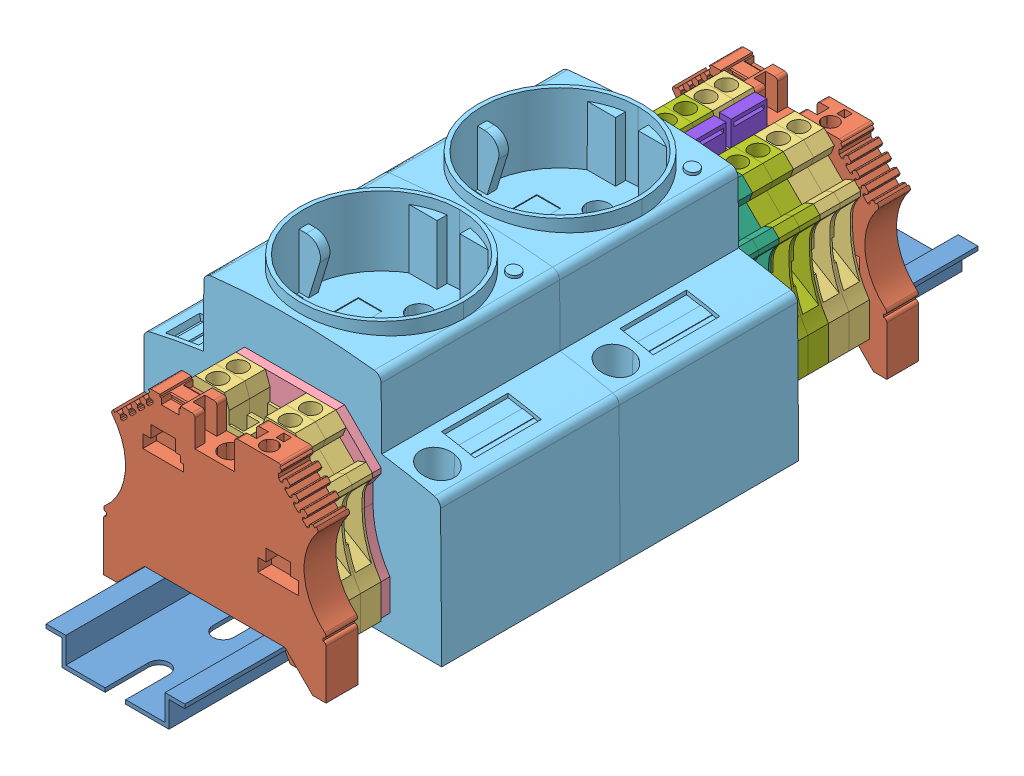
SolidWorks assembly Baugruppe4, configuration Standard. Lengths in mm.
Overall size (75.48 67.56 200).
17 component instances, 8 part files, 51 mates.
Components (placement in the parent):
- Hutschiene-1: Hutschiene [200] at (-17.5 -7.5 -200) size (35 7.5 200)
- WEW_35_2-1: WEW_35_2 [Standard] at (-45.49 -7 -33) x (0 0 1) z (0 1 0) size (8 56.1 46.5)
- UT_2.5-1: UT_2.5 [Standard] at (-48.9989 10.6178 -33) x (0.992546 -0.121869 0) z (0 0 1) size (49.27 50.96 5.15)
- UT_2.5-2: UT_2.5 [Standard] at (-48.9989 10.6178 -38.15) x (0.992546 -0.121869 0) z (0 0 1) size (49.27 50.96 5.15)
- D_UT_2.5_10-1: D_UT_2.5_10 [Standard] at (-46.7297 58.45 -45.5) size (47 39.8 2.2)
- EO_CF_UT_LED-1: EO_CF_UT_LED [Standard] at (-87.6914 -21.0563 -70.25) size (75.48 61.64 45)
- EO_CF_UT_LED-2: EO_CF_UT_LED [Standard] at (-87.6914 -21.0563 -115.25) size (75.48 61.64 45)
- UT_2.5_PE-1: UT_2.5_PE [Standard] at (-48.9989 10.6178 -135.5) x (0.992546 -0.121869 0) z (0 0 1) size (49.27 50.96 5.15)
- UT_2.5_PE-2: UT_2.5_PE [Standard] at (-48.9989 10.6178 -140.65) x (0.992546 -0.121869 0) z (0 0 1) size (49.27 50.96 5.15)
- UT_2.5_BU-1: UT_2.5_BU [Standard] at (-48.9989 10.6178 -145.8) x (0.992546 -0.121869 0) z (0 0 1) size (49.27 50.96 5.15)
- UT_2.5_BU-2: UT_2.5_BU [Standard] at (-48.9989 10.6178 -150.95) x (0.992546 -0.121869 0) z (0 0 1) size (49.27 50.96 5.15)
- UT_2.5-3: UT_2.5 [Standard] at (-48.9989 10.6178 -156.1) x (0.992546 -0.121869 0) z (0 0 1) size (49.27 50.96 5.15)
- UT_2.5-4: UT_2.5 [Standard] at (-48.9989 10.6178 -161.25) x (0.992546 -0.121869 0) z (0 0 1) size (49.27 50.96 5.15)
- WEW_35_2-2: WEW_35_2 [Standard] at (-45.49 -7 -174.4) x (0 0 1) z (0 1 0) size (8 56.1 46.5)
- FBS_2-5-1: FBS_2-5 [Standard] at (-24.4072 49.175 -194.335) size (3 22.98 9)
- FBS_2-5-2: FBS_2-5 [Standard] at (-24.4072 49.175 -204.635) size (3 22.98 9)
- FBS_2-5-3: FBS_2-5 [Standard] at (-24.4072 49.175 -214.935) size (3 22.98 9)
Mates (geometry in assembly coordinates):
- Deckungsgleich1: coincident aligned: plane of Hutschiene-1 through (-17.5 -7.5 0) normal (0 0 1); plane of assembly through (0 0 0) normal (0 0 1)
- Deckungsgleich2: coincident aligned: plane of Hutschiene-1 through (0 -1 0) normal (1 0 0); plane of assembly through (0 0 0) normal (1 0 0)
- Deckungsgleich3: coincident aligned: plane of Hutschiene-1 through (-30 0 0) normal (0 1 0); plane of assembly through (0 0 0) normal (0 1 0)
- Deckungsgleich4: coincident anti-aligned: plane of Hutschiene-1 through (0 0 0) normal (0 1 0); plane of WEW_35_2-1 through (0.26 0 -11.7033) normal (0 -1 0)
- Tangential2: tangent anti-aligned: cylinder of WEW_35_2-1 through (-37 -1.4 -15.7033) axis (0 0 1) radius 2; plane of Hutschiene-1 through (-35 0 0) normal (-1 0 0)
- Deckungsgleich8: coincident anti-aligned: plane of Hutschiene-1 through (-30 0 0) normal (0 1 0); plane of UT_2.5-1 through (-8 0 -19.7033) normal (0 -1 0)
- Deckungsgleich9: coincident anti-aligned: plane of Hutschiene-1 through (-30 0 0) normal (0 1 0); plane of UT_2.5-2 through (-8 0 -24.8533) normal (0 -1 0)
- Deckungsgleich10: coincident anti-aligned: plane of Hutschiene-1 through (-35 0 0) normal (-1 0 0); plane of UT_2.5-2 through (-35 -0.3 -24.8533) normal (1 0 0)
- Deckungsgleich11: coincident anti-aligned: plane of Hutschiene-1 through (-35 0 0) normal (-1 0 0); plane of UT_2.5-1 through (-35 -0.3 -19.7033) normal (1 0 0)
- Deckungsgleich12: coincident anti-aligned: plane of WEW_35_2-1 through (-17.44 0 -19.7033) normal (0 0 -1); plane of UT_2.5-1 through (-0.3 0 -19.7033) normal (0 0 1)
- Deckungsgleich13: coincident anti-aligned: plane of UT_2.5-1 through (-0.3 0 -24.8533) normal (0 0 -1); plane of UT_2.5-2 through (-0.3 0 -24.8533) normal (0 0 1)
- Deckungsgleich14: coincident anti-aligned: plane of UT_2.5-2 through (-0.3 0 -30.0033) normal (0 0 -1); plane of D_UT_2.5_10-1 through (-31.6534 31.331 -30.0033) normal (0 0 1)
- Deckungsgleich15: coincident aligned: plane of UT_2.5-2 through (-32.9741 37.4259 -24.8533) normal (-0.707107 0.707107 0); plane of D_UT_2.5_10-1 through (-30.4 40 -31.1033) normal (-0.707107 0.707107 0)
- Deckungsgleich16: coincident aligned: plane of UT_2.5-2 through (-30.4 40 -24.8533) normal (0 1 0); plane of D_UT_2.5_10-1 through (-23 40 -30.6033) normal (0 1 0)
- Deckungsgleich17: coincident anti-aligned: plane of D_UT_2.5_10-1 through (8.626 -3.78 -32.2033) normal (0 0 -1); plane of EO_CF_UT_LED-1 through (-18.35 2.45 -32.2033) normal (0 0 1)
- Deckungsgleich18: coincident anti-aligned: plane of EO_CF_UT_LED-1 through (-18.35 2.45 -77.2033) normal (0 0 -1); plane of EO_CF_UT_LED-2 through (-18.35 2.45 -77.2033) normal (0 0 1)
- Deckungsgleich19: coincident anti-aligned: plane of Hutschiene-1 through (0 0 0) normal (0 1 0); plane of EO_CF_UT_LED-1 through (-54.65 0 -59.1033) normal (0 -1 0)
- Deckungsgleich20: coincident anti-aligned: plane of Hutschiene-1 through (0 0 0) normal (0 1 0); plane of EO_CF_UT_LED-2 through (-54.65 0 -104.1033) normal (0 -1 0)
- Deckungsgleich21: coincident anti-aligned: plane of Hutschiene-1 through (-35 0 0) normal (-1 0 0); plane of EO_CF_UT_LED-2 through (-35 -41.451 -108.4533) normal (1 0 0)
- Deckungsgleich22: coincident anti-aligned: plane of Hutschiene-1 through (-35 0 0) normal (-1 0 0); plane of EO_CF_UT_LED-1 through (-35 -41.451 -63.4533) normal (1 0 0)
- Deckungsgleich23: coincident anti-aligned: plane of EO_CF_UT_LED-2 through (-18.35 2.45 -122.2033) normal (0 0 -1); plane of UT_2.5_PE-1 through (-0.3 0 -122.2033) normal (0 0 1)
- Deckungsgleich24: coincident anti-aligned: plane of UT_2.5_PE-1 through (-0.3 0 -127.3533) normal (0 0 -1); plane of UT_2.5_PE-2 through (-0.3 0 -127.3533) normal (0 0 1)
- Deckungsgleich25: coincident anti-aligned: plane of UT_2.5_PE-2 through (-0.3 0 -132.5033) normal (0 0 -1); plane of UT_2.5_BU-1 through (-0.3 0 -132.5033) normal (0 0 1)
- Deckungsgleich26: coincident anti-aligned: plane of UT_2.5_BU-1 through (-0.3 0 -137.6533) normal (0 0 -1); plane of UT_2.5_BU-2 through (-0.3 0 -137.6533) normal (0 0 1)
- Deckungsgleich27: coincident anti-aligned: plane of UT_2.5_BU-2 through (-0.3 0 -142.8033) normal (0 0 -1); plane of UT_2.5-3 through (-0.3 0 -142.8033) normal (0 0 1)
- Deckungsgleich28: coincident anti-aligned: plane of UT_2.5-3 through (-0.3 0 -147.9533) normal (0 0 -1); plane of UT_2.5-4 through (-0.3 0 -147.9533) normal (0 0 1)
- Deckungsgleich29: coincident anti-aligned: plane of UT_2.5-4 through (-0.3 0 -153.1033) normal (0 0 -1); plane of WEW_35_2-2 through (-17.44 0 -153.1033) normal (0 0 1)
- Deckungsgleich30: coincident anti-aligned: plane of Hutschiene-1 through (0 0 0) normal (0 1 0); plane of UT_2.5_PE-1 through (-8 0 -122.2033) normal (0 -1 0)
- Deckungsgleich31: coincident anti-aligned: plane of Hutschiene-1 through (0 0 0) normal (0 1 0); plane of UT_2.5_PE-2 through (-8 0 -127.3533) normal (0 -1 0)
- Deckungsgleich32: coincident anti-aligned: plane of Hutschiene-1 through (0 0 0) normal (0 1 0); plane of UT_2.5_BU-1 through (-8 0 -132.5033) normal (0 -1 0)
- Deckungsgleich33: coincident anti-aligned: plane of Hutschiene-1 through (0 0 0) normal (0 1 0); plane of UT_2.5_BU-2 through (-8 0 -137.6533) normal (0 -1 0)
- Deckungsgleich34: coincident anti-aligned: plane of Hutschiene-1 through (0 0 0) normal (0 1 0); plane of UT_2.5-3 through (-8 0 -142.8033) normal (0 -1 0)
- Deckungsgleich35: coincident anti-aligned: plane of Hutschiene-1 through (0 0 0) normal (0 1 0); plane of UT_2.5-4 through (-8 0 -147.9533) normal (0 -1 0)
- Deckungsgleich36: coincident anti-aligned: plane of Hutschiene-1 through (0 0 0) normal (0 1 0); plane of WEW_35_2-2 through (0.26 0 -153.1033) normal (0 -1 0)
- Deckungsgleich37: coincident anti-aligned: plane of Hutschiene-1 through (-35 0 0) normal (-1 0 0); plane of UT_2.5_PE-1 through (-35 -0.3 -122.2033) normal (1 0 0)
- Deckungsgleich38: coincident anti-aligned: plane of Hutschiene-1 through (-35 0 0) normal (-1 0 0); plane of UT_2.5_PE-2 through (-35 -0.3 -127.3533) normal (1 0 0)
- Deckungsgleich39: coincident anti-aligned: plane of Hutschiene-1 through (-35 0 0) normal (-1 0 0); plane of UT_2.5_BU-1 through (-35 -0.3 -132.5033) normal (1 0 0)
- Deckungsgleich40: coincident anti-aligned: plane of Hutschiene-1 through (-35 0 0) normal (-1 0 0); plane of UT_2.5_BU-2 through (-35 -0.3 -137.6533) normal (1 0 0)
- Deckungsgleich41: coincident anti-aligned: plane of Hutschiene-1 through (-35 0 0) normal (-1 0 0); plane of UT_2.5-3 through (-35 -0.3 -142.8033) normal (1 0 0)
- Deckungsgleich42: coincident anti-aligned: plane of Hutschiene-1 through (-35 0 0) normal (-1 0 0); plane of UT_2.5-4 through (-35 -0.3 -147.9533) normal (1 0 0)
- Tangential3: tangent anti-aligned: plane of Hutschiene-1 through (-35 0 0) normal (-1 0 0); cylinder of WEW_35_2-2 through (-37 -1.4 -157.1033) axis (0 0 1) radius 2
- Deckungsgleich43: coincident anti-aligned: plane of UT_2.5_PE-1 through (-18.65 21.85 -122.6783) normal (0 0 -1); plane of FBS_2-5-1 through (-18.8 39.7 -122.6783) normal (0 0 1)
- Deckungsgleich44: coincident anti-aligned: plane of UT_2.5_PE-1 through (-21.8 36.703 -122.2033) normal (1 0 0); plane of FBS_2-5-1 through (-21.8 41.9423 -156.9383) normal (-1 0 0)
- Deckungsgleich45: coincident anti-aligned: plane of UT_2.5_BU-1 through (-18.65 21.85 -132.9783) normal (0 0 -1); plane of FBS_2-5-2 through (-18.8 39.7 -132.9783) normal (0 0 1)
- Deckungsgleich46: coincident anti-aligned: plane of UT_2.5_BU-1 through (-21.8 36.703 -132.5033) normal (1 0 0); plane of FBS_2-5-2 through (-21.8 41.9423 -167.2383) normal (-1 0 0)
- Deckungsgleich47: coincident anti-aligned: plane of UT_2.5-3 through (-21.8 36.703 -142.8033) normal (1 0 0); plane of FBS_2-5-3 through (-21.8 41.9423 -177.5383) normal (-1 0 0)
- Deckungsgleich48: coincident anti-aligned: plane of UT_2.5-3 through (-18.65 21.85 -143.2783) normal (0 0 -1); plane of FBS_2-5-3 through (-18.8 39.7 -143.2783) normal (0 0 1)
- Deckungsgleich49: coincident aligned: plane of UT_2.5-3 through (-30.4 40 -142.8033) normal (0 1 0); plane of FBS_2-5-1 through (-18.8 40 -102.1783) normal (0 1 0)
- Deckungsgleich50: coincident aligned: plane of UT_2.5-3 through (-30.4 40 -142.8033) normal (0 1 0); plane of FBS_2-5-3 through (-18.8 40 -122.7783) normal (0 1 0)
- Deckungsgleich51: coincident aligned: plane of UT_2.5_BU-1 through (-30.4 40 -132.5033) normal (0 1 0); plane of FBS_2-5-2 through (-18.8 40 -112.4783) normal (0 1 0)
- Abstand1: distance = 25 mm aligned: plane of WEW_35_2-1 through (-17.44 0 -25) normal (0 0 1); plane of Hutschiene-1 through (-17.5 -7.5 0) normal (0 0 1)
